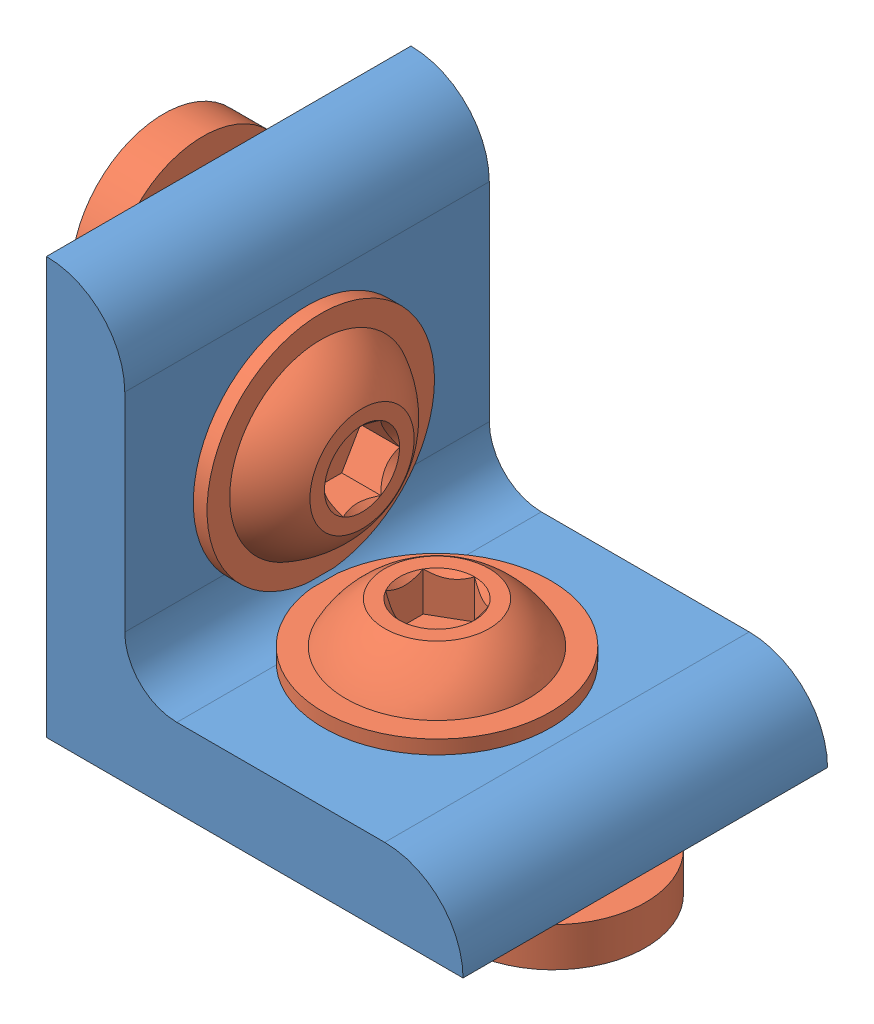
SolidWorks assembly BracketSubAssembly, configuration Default. Lengths in mm.
Overall size (33.74 33.74 22.23).
3 component instances, 2 part files, 4 mates.
Components (placement in the parent):
- 47065T236_ALUMINUM T-SLOTTED FRAMING EXTRUSION-1: 47065T236_ALUMINUM T-SLOTTED FRAMING EXTRUSION [47065T236] at (-1.9629 3.4611 16.8596) size (25.4 25.4 22.23)
- 47065T142_ALUMINUM T-SLOTTED FRAMING EXTRUSION-3: 47065T142_ALUMINUM T-SLOTTED FRAMING EXTRUSION [47065T142] at (2.8123 16.1611 16.8596) x (0 -1 0) z (0 0 1) size (25.4 16.7 13.87)
- 47065T142_ALUMINUM T-SLOTTED FRAMING EXTRUSION-4: 47065T142_ALUMINUM T-SLOTTED FRAMING EXTRUSION [47065T142] at (10.7371 8.2363 16.8596) size (25.4 16.7 13.87)
Mates (geometry in assembly coordinates):
- Coincident6: coincident aligned: line of 47065T236_ALUMINUM T-SLOTTED FRAMING EXTRUSION-1 through (2.8123 16.1611 16.8596) axis (-1 0 0); line of 47065T142_ALUMINUM T-SLOTTED FRAMING EXTRUSION-3 through (3.6505 16.1611 16.8596) axis (-1 0 0)
- Coincident7: coincident anti-aligned: plane of 47065T236_ALUMINUM T-SLOTTED FRAMING EXTRUSION-1 through (2.8123 24.0859 27.9721) normal (1 0 0); plane of 47065T142_ALUMINUM T-SLOTTED FRAMING EXTRUSION-3 through (2.8123 9.2269 16.8596) normal (-1 0 0)
- Coincident9: coincident: plane of 47065T236_ALUMINUM T-SLOTTED FRAMING EXTRUSION-1 through (5.9873 8.2363 27.9721) normal (0 1 0); plane of 47065T142_ALUMINUM T-SLOTTED FRAMING EXTRUSION-4 through (30.7447 8.2363 22.6234) normal (0 -1 0)
- Coincident10: coincident aligned: line of 47065T236_ALUMINUM T-SLOTTED FRAMING EXTRUSION-1 through (10.7371 8.2363 16.8596) axis (0 -1 0); line of 47065T142_ALUMINUM T-SLOTTED FRAMING EXTRUSION-4 through (10.7371 9.0745 16.8596) axis (0 -1 0)
